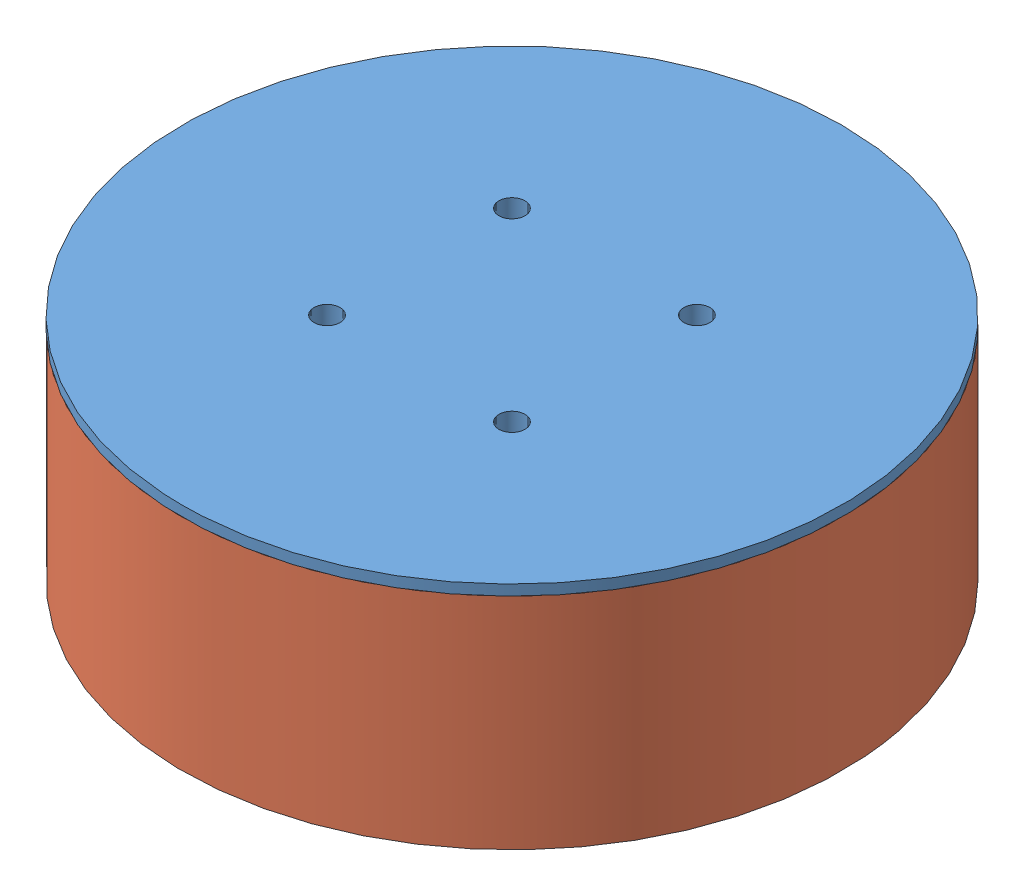
SolidWorks assembly Motor Assm, configuration Default. Lengths in mm.
Overall size (70.86 22 70.86).
2 component instances, 2 part files, 2 mates.
Components (placement in the parent):
- Mock Motor Bottom-1: Mock Motor Bottom [Default] at (28.2069 26.1288 46.7306) size (63 11 63)
- Mock Motor Top-1: Mock Motor Top [Default] at (28.2069 36.1288 46.7306) x (0.133697 0 0.991022) z (0.991022 0 -0.133697) size (63 21 63)
Mates (geometry in assembly coordinates):
- Coincident3: coincident: plane of Mock Motor Bottom-1 through (28.2069 26.1288 46.7306) normal (0 -1 0); plane of Mock Motor Top-1 through (28.2069 26.1288 46.7306) normal (0 1 0)
- Concentric3: concentric anti-aligned: cylinder of Mock Motor Bottom-1 through (28.2069 36.1288 46.7306) axis (0 -1 0) radius 27; cylinder of Mock Motor Top-1 through (28.2069 26.1288 46.7306) axis (0 1 0) radius 27
